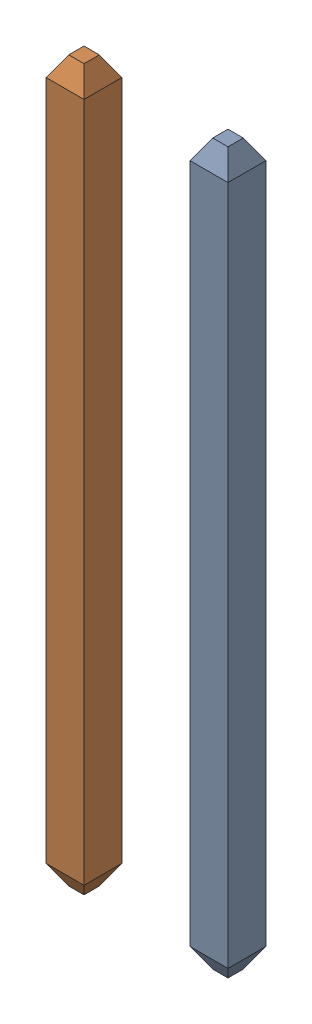
SolidWorks assembly User Library-LCD1602 with I2C_User Library-1x4 TH Pitch 2_54mm, configuration Default. Lengths in mm.
Overall size (3.21 12.7 0.67).
2 component instances, 1 part files, 0 mates.
Components (placement in the parent):
- User Library-LCD1602 with I2C_pin-1: User Library-LCD1602 with I2C_pin [Default] at (-1.29 -3.5 0.02) size (0.67 12.7 0.67)
- User Library-LCD1602 with I2C_pin-2: User Library-LCD1602 with I2C_pin [Default] at (-3.83 -3.5 0.02) size (0.67 12.7 0.67)
